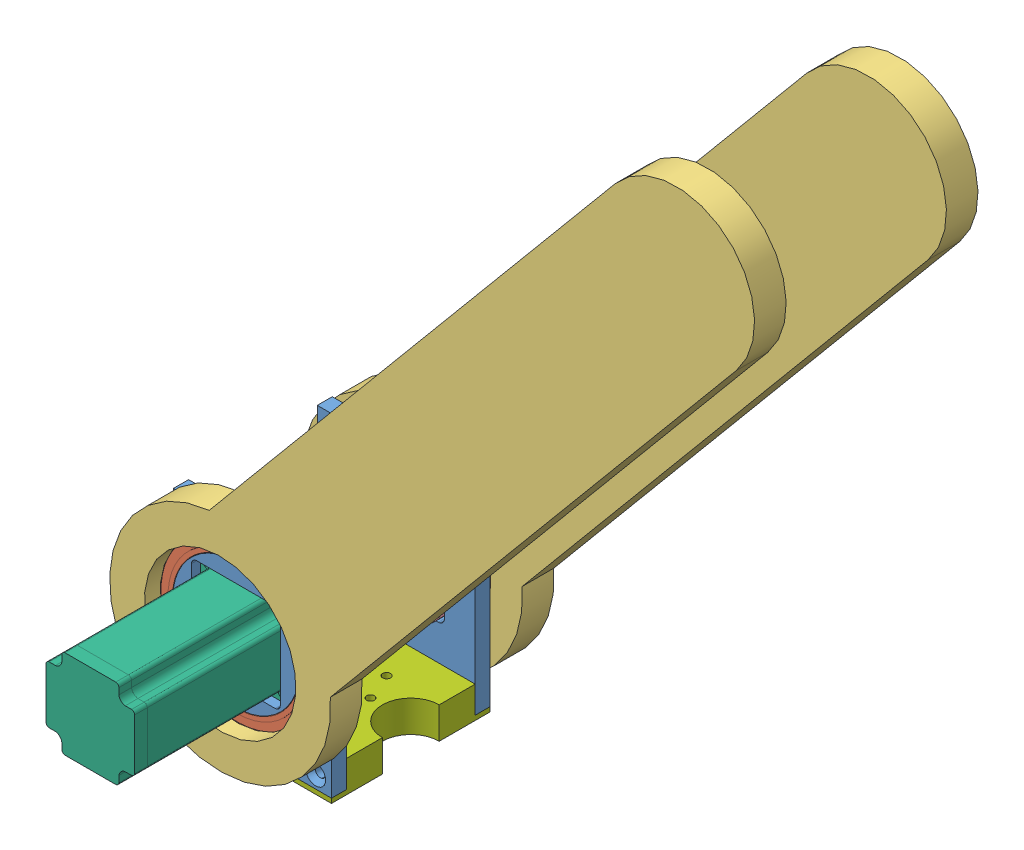
SolidWorks assembly Assemblage1, configuration Défaut. Lengths in mm.
Overall size (472.9 527.19 236.73).
11 component instances, 7 part files, 18 mates.
Components (placement in the parent):
- Bride-1: Bride [Défaut] at (-30.2032 -8.4547 -10) size (100 120 20)
- 80x100x10 bearing-1: 80x100x10 bearing [Défaut] at (-30.2032 -8.4547 0) x (-0.979658 0.200673 0) z (0 0 1) size (100 100 10)
- Bras-1: Bras [Défaut] at (-30.2032 -8.4547 20) x (-0.641158 -0.767408 0) z (0 0 -1) size (570 140 20)
- Axe2-1: Axe2 [Défaut] at (-50.0148 -46.4351 -68.25) x (-1 0 0) z (0 0 -1) size (77.83 77.83 236.73) (flexible)
  - PLF60_50_1_reducer-1: PLF60_50_1_reducer [Défaut] at (-19.8116 37.9804 -66.25) size (77.83 77.83 132.5)
  - D14_Hub-1: D14_Hub [Défaut] at (-19.8116 37.9804 63.7049) x (-1 0 0) z (0 -1 0) size (56.8 26.4 56.8)
  - Nema23x100-1: Nema23x100 [Défaut] at (-19.8116 37.9804 -170.458) size (56.45 56.45 126.22)
- Bride-2: Bride [fixation moteur] at (-30.2032 -8.4547 -91.5) x (-1 0 0) z (0 0 -1) size (100 120 20)
- 80x100x10 bearing-2: 80x100x10 bearing [Défaut] at (-30.2032 -8.4547 -111.5) x (-0.987152 0.159783 0) z (0 0 1) size (100 100 10)
- Bras-2: Bras [Défaut] at (-30.2032 -8.4547 -121.5) x (-0.641158 -0.767408 0) z (0 0 1) size (570 140 20)
- EntretoiseInf-1: EntretoiseInf [Défaut] at (-30.2032 -81.3547 -50.75) x (0 0 -1) z (1 0 0) size (100.5 20 100)
Mates (geometry in assembly coordinates):
- Coaxiale1: concentric aligned: cylinder of Bride-1 through (-30.2032 -8.4547 10) axis (0 0 -1) radius 40; cylinder of 80x100x10 bearing-1 through (-30.2032 -8.4547 10) axis (0 0 -1) radius 40
- Coïncidente1: coincident anti-aligned: plane of Bride-1 through (-30.2032 -8.4547 0) normal (0 0 1); plane of 80x100x10 bearing-1 through (-30.2032 -8.4547 0) normal (0 0 -1)
- Coaxiale2: concentric anti-aligned: cylinder of 80x100x10 bearing-1 through (-30.2032 -8.4547 10) axis (0 0 -1) radius 50; cylinder of Bras-1 through (-30.2032 -8.4547 0) axis (0 0 1) radius 50
- Coïncidente2: coincident anti-aligned: plane of 80x100x10 bearing-1 through (-30.2032 -8.4547 10) normal (0 0 1); plane of Bras-1 through (-30.2032 -8.4547 10) normal (0 0 -1)
- Coïncidente3: coincident anti-aligned: plane of Bride-1 through (-30.2032 -8.4547 -2) normal (0 0 -1); plane of Axe2-1/PLF60_50_1_reducer-1 through (-30.2032 -8.4547 -2) normal (0 0 1)
- Coaxiale3: concentric aligned: cylinder of Bras-1 through (-30.2032 -8.4547 10) axis (0 0 1) radius 48; cylinder of Axe2-1/PLF60_50_1_reducer-1 through (-30.2032 -8.4547 -88.5) axis (0 0 1) radius 29.5
- Parallèle1: parallel anti-aligned: plane of Bride-1 through (-60.8532 22.1953 -1) normal (0 -1 0); plane of Axe2-1/PLF60_50_1_reducer-1 through (-60.2032 21.5453 -24) normal (0 1 0)
- Coaxiale4: concentric aligned: cylinder of Axe2-1/PLF60_50_1_reducer-1 through (-30.2032 -8.4547 -88.5) axis (0 0 1) radius 29.5; cylinder of Bride-2 through (-30.2032 -8.4547 -111.5) axis (0 0 1) radius 40
- Coïncidente5: coincident anti-aligned: plane of Axe2-1/PLF60_50_1_reducer-1 through (-30.2032 -8.4547 -99.5) normal (0 0 -1); plane of Bride-2 through (-30.2032 -8.4547 -99.5) normal (0 0 1)
- Coaxiale5: concentric anti-aligned: cylinder of Bride-2 through (-30.2032 -8.4547 -111.5) axis (0 0 1) radius 40; cylinder of 80x100x10 bearing-2 through (-30.2032 -8.4547 -101.5) axis (0 0 -1) radius 40
- Coïncidente7: coincident anti-aligned: plane of Bride-2 through (-30.2032 -8.4547 -101.5) normal (0 0 -1); plane of 80x100x10 bearing-2 through (-30.2032 -8.4547 -101.5) normal (0 0 1)
- Coaxiale6: concentric aligned: cylinder of 80x100x10 bearing-2 through (-30.2032 -8.4547 -101.5) axis (0 0 -1) radius 50; cylinder of Bras-2 through (-30.2032 -8.4547 -101.5) axis (0 0 -1) radius 50
- Coïncidente8: coincident anti-aligned: plane of 80x100x10 bearing-2 through (-30.2032 -8.4547 -111.5) normal (0 0 -1); plane of Bras-2 through (-30.2032 -8.4547 -111.5) normal (0 0 1)
- Coaxiale7: concentric anti-aligned: cylinder of Bras-1 through (258.3181 336.8792 0) axis (0 0 1) radius 50; cylinder of Bras-2 through (258.3181 336.8792 -101.5) axis (0 0 -1) radius 50
- Parallèle2: parallel anti-aligned: plane of Axe2-1/PLF60_50_1_reducer-1 through (-60.2032 21.5453 -99.5) normal (0 1 0); plane of Bride-2 through (0.4468 22.1953 -100.5) normal (0 -1 0)
- Coïncidente9: coincident anti-aligned: plane of Bride-2 through (-30.2032 -8.4547 -91.5) normal (0 0 1); plane of EntretoiseInf-1 through (19.7968 -181.8049 -91.5) normal (0 0 -1)
- Coaxiale8: concentric aligned: cylinder of Bride-2 through (9.7968 -70.4547 -101) axis (0 0 -1) radius 3.3; cylinder of EntretoiseInf-1 through (9.7968 -70.4547 -75.5) axis (0 0 -1) radius 2.5
- Coaxiale9: concentric aligned: cylinder of Bride-2 through (-70.2032 -70.4547 -101) axis (0 0 -1) radius 3.3; cylinder of EntretoiseInf-1 through (-70.2032 -70.4547 -75.5) axis (0 0 -1) radius 2.5
